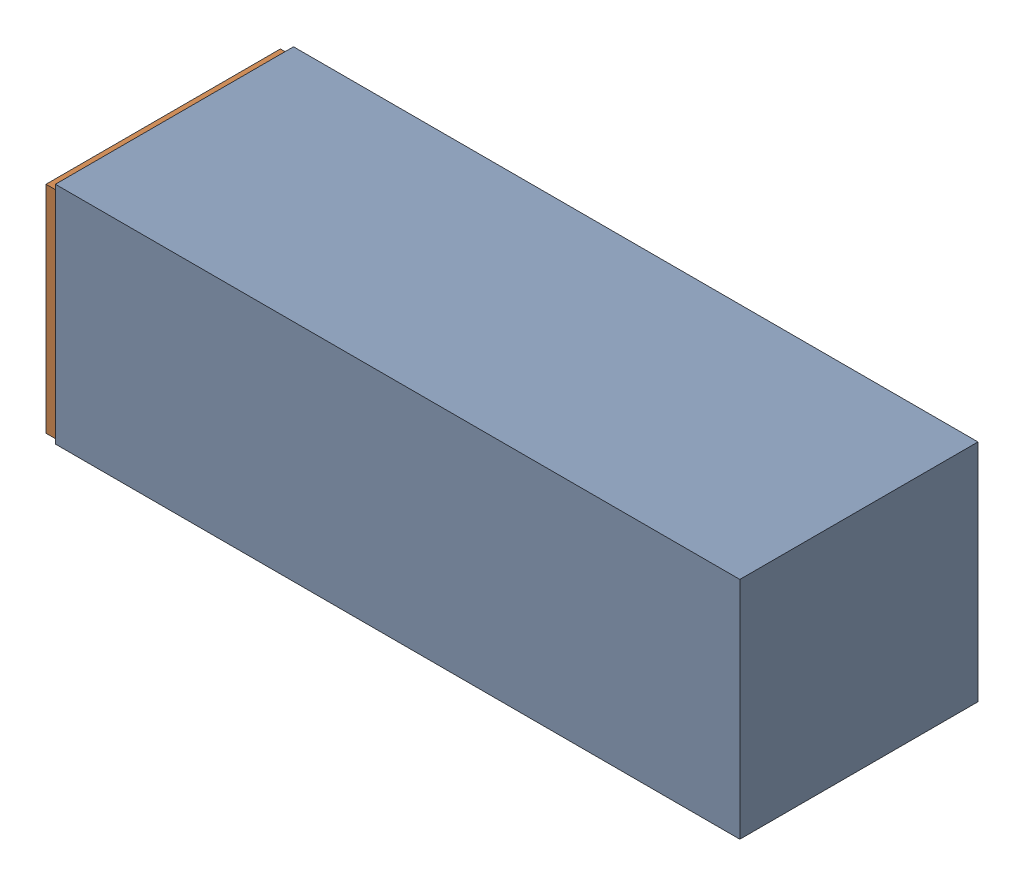
SolidWorks assembly H3, configuration Default. Lengths in mm.
Overall size (46.99 15.24 16.13).
4 component instances, 2 part files, 0 mates.
Components (placement in the parent):
- 407985440-1: 407985440 [Default] at (47.1043 24.3586 -16.5329) size (46.35 15.24 16.13)
  - Extruded_4-1: Extruded_4 [Default] at origin size (46.35 15.24 16.13)
- 407985312-1: 407985312 [Default] at (23.6093 24.3586 -16.2789) size (0.64 14.61 15.88)
  - Extruded_5-1: Extruded_5 [Default] at origin size (0.64 14.61 15.88)
